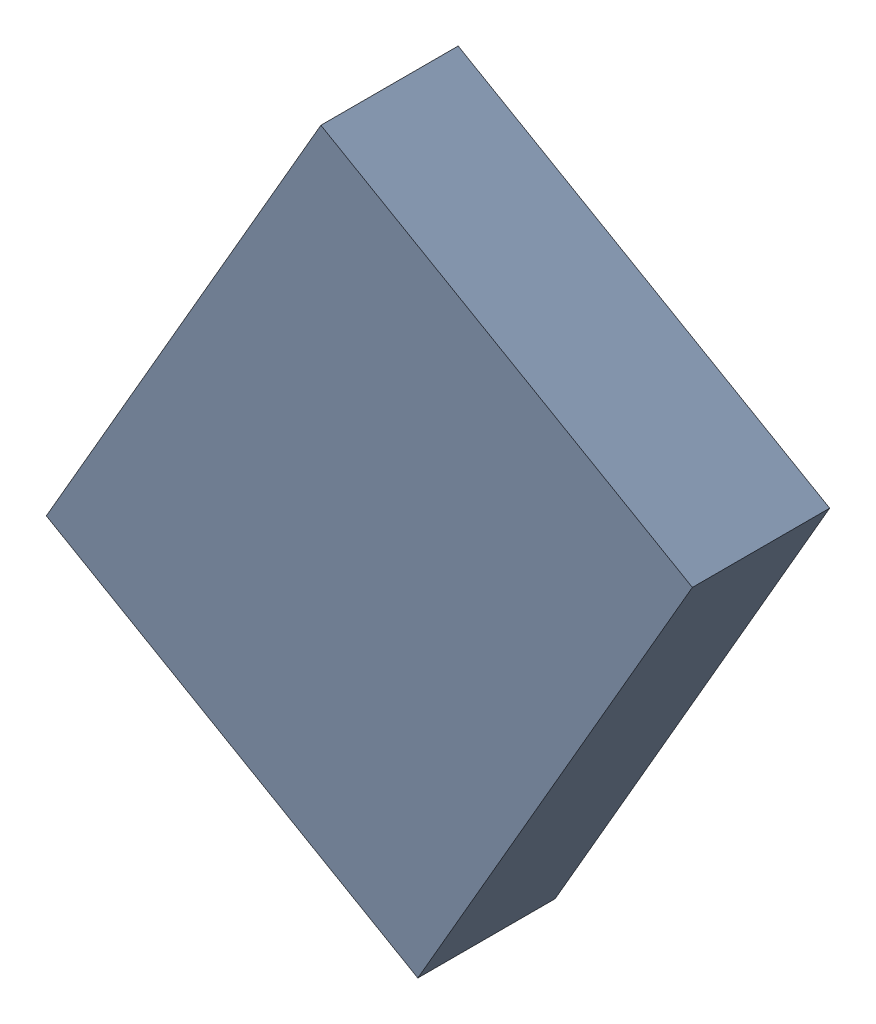
SolidWorks assembly X_TDA_1_TDA6, configuration Standard. Lengths in mm.
Overall size (3.77 4.02 0.8).
2 component instances, 1 part files, 0 mates.
Components (placement in the parent):
- 668293800-1: 668293800 [Standard] at (-35.3942 22.6879 0) size (3.77 4.02 0.8)
  - Extruded-1: Extruded [Standard] at origin size (3.77 4.02 0.8)
